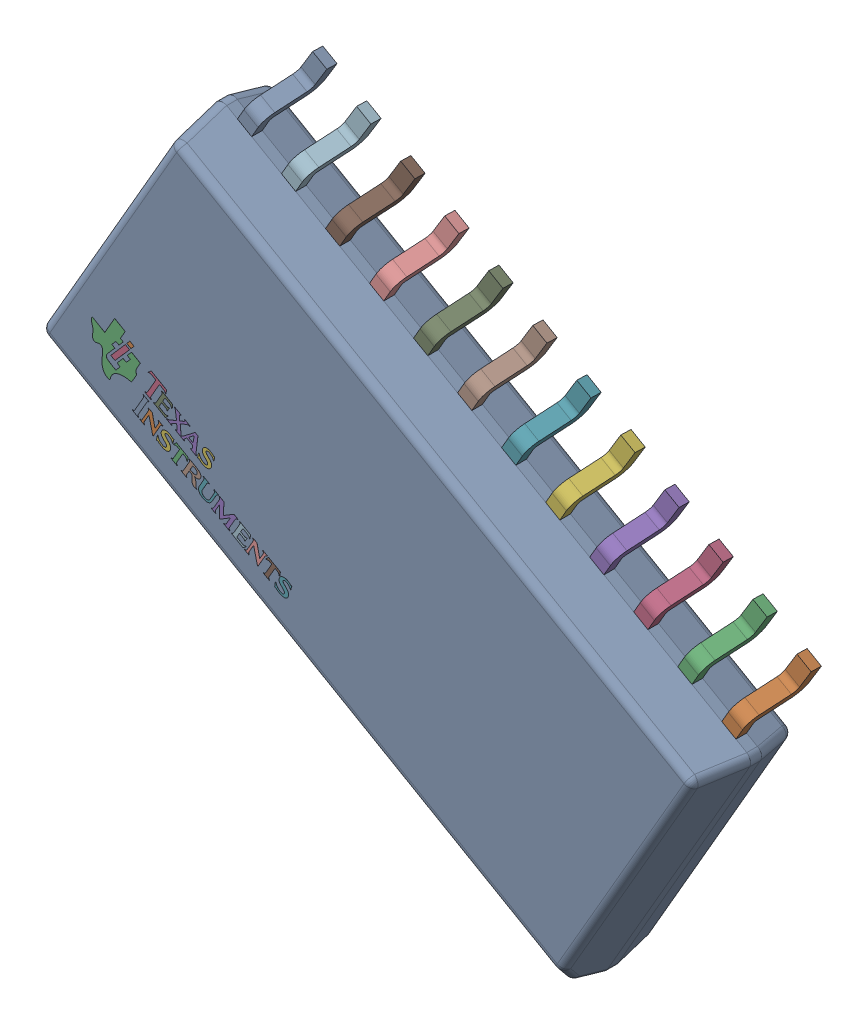
SolidWorks assembly U7, configuration Défaut. Lengths in mm.
Overall size (18.51 16.65 2.65).
28 component instances, 4 part files, 0 mates.
Components (placement in the parent):
- IC_Texas_Instruments_CD74HC4067M96_eec-1: IC_Texas_Instruments_CD74HC4067M96_eec [Défaut] at (22.368 -19.247 0) x (-0.5 -0.866025 0) z (0 0 1) size (10.34 15.4 2.65)
  - BODY-SO-1: BODY-SO [Défaut] at (0 0 1.0825) x (0 1 0) z (1 0 0) size (15.4 2.45 7.5)
  - LEAD-SO-1: LEAD-SO [Défaut] at (4.315 6.985 0.25) x (0 1 0) z (1 0 0) size (0.41 1.43 1.42)
  - LEAD-SO-2: LEAD-SO [Défaut] at (4.315 5.715 0.25) x (0 1 0) z (1 0 0) size (0.41 1.43 1.42)
  - LEAD-SO-3: LEAD-SO [Défaut] at (4.315 4.445 0.25) x (0 1 0) z (1 0 0) size (0.41 1.43 1.42)
  - LEAD-SO-4: LEAD-SO [Défaut] at (4.315 3.175 0.25) x (0 1 0) z (1 0 0) size (0.41 1.43 1.42)
  - LEAD-SO-5: LEAD-SO [Défaut] at (4.315 1.905 0.25) x (0 1 0) z (1 0 0) size (0.41 1.43 1.42)
  - LEAD-SO-6: LEAD-SO [Défaut] at (4.315 0.635 0.25) x (0 1 0) z (1 0 0) size (0.41 1.43 1.42)
  - LEAD-SO-7: LEAD-SO [Défaut] at (4.315 -0.635 0.25) x (0 1 0) z (1 0 0) size (0.41 1.43 1.42)
  - LEAD-SO-8: LEAD-SO [Défaut] at (4.315 -1.905 0.25) x (0 1 0) z (1 0 0) size (0.41 1.43 1.42)
  - LEAD-SO-9: LEAD-SO [Défaut] at (4.315 -3.175 0.25) x (0 1 0) z (1 0 0) size (0.41 1.43 1.42)
  - LEAD-SO-10: LEAD-SO [Défaut] at (4.315 -4.445 0.25) x (0 1 0) z (1 0 0) size (0.41 1.43 1.42)
  - LEAD-SO-11: LEAD-SO [Défaut] at (4.315 -5.715 0.25) x (0 1 0) z (1 0 0) size (0.41 1.43 1.42)
  - LEAD-SO-12: LEAD-SO [Défaut] at (4.315 -6.985 0.25) x (0 1 0) z (1 0 0) size (0.41 1.43 1.42)
  - LEAD-SO-13: LEAD-SO [Défaut] at (-4.315 6.985 0.25) x (0 -1 0) z (-1 0 0) size (0.41 1.43 1.42)
  - LEAD-SO-14: LEAD-SO [Défaut] at (-4.315 5.715 0.25) x (0 -1 0) z (-1 0 0) size (0.41 1.43 1.42)
  - LEAD-SO-15: LEAD-SO [Défaut] at (-4.315 4.445 0.25) x (0 -1 0) z (-1 0 0) size (0.41 1.43 1.42)
  - LEAD-SO-16: LEAD-SO [Défaut] at (-4.315 3.175 0.25) x (0 -1 0) z (-1 0 0) size (0.41 1.43 1.42)
  - LEAD-SO-17: LEAD-SO [Défaut] at (-4.315 1.905 0.25) x (0 -1 0) z (-1 0 0) size (0.41 1.43 1.42)
  - LEAD-SO-18: LEAD-SO [Défaut] at (-4.315 0.635 0.25) x (0 -1 0) z (-1 0 0) size (0.41 1.43 1.42)
  - LEAD-SO-19: LEAD-SO [Défaut] at (-4.315 -0.635 0.25) x (0 -1 0) z (-1 0 0) size (0.41 1.43 1.42)
  - LEAD-SO-20: LEAD-SO [Défaut] at (-4.315 -1.905 0.25) x (0 -1 0) z (-1 0 0) size (0.41 1.43 1.42)
  - LEAD-SO-21: LEAD-SO [Défaut] at (-4.315 -3.175 0.25) x (0 -1 0) z (-1 0 0) size (0.41 1.43 1.42)
  - LEAD-SO-22: LEAD-SO [Défaut] at (-4.315 -4.445 0.25) x (0 -1 0) z (-1 0 0) size (0.41 1.43 1.42)
  - LEAD-SO-23: LEAD-SO [Défaut] at (-4.315 -5.715 0.25) x (0 -1 0) z (-1 0 0) size (0.41 1.43 1.42)
  - LEAD-SO-24: LEAD-SO [Défaut] at (-4.315 -6.985 0.25) x (0 -1 0) z (-1 0 0) size (0.41 1.43 1.42)
  - Texas Logo Yury-1: Texas Logo Yury [Défaut] at (2.174 -7.1221 2.551) x (0 1 0) z (0 0 1) size (1.32 1.29 0.11)
  - Texas Logo Yury - Copy-1: Texas Logo Yury - Copy [Défaut] at (2.0641 -7.1534 2.551) x (0 1 0) z (0 0 1) size (4.61 1.2 0.1)
